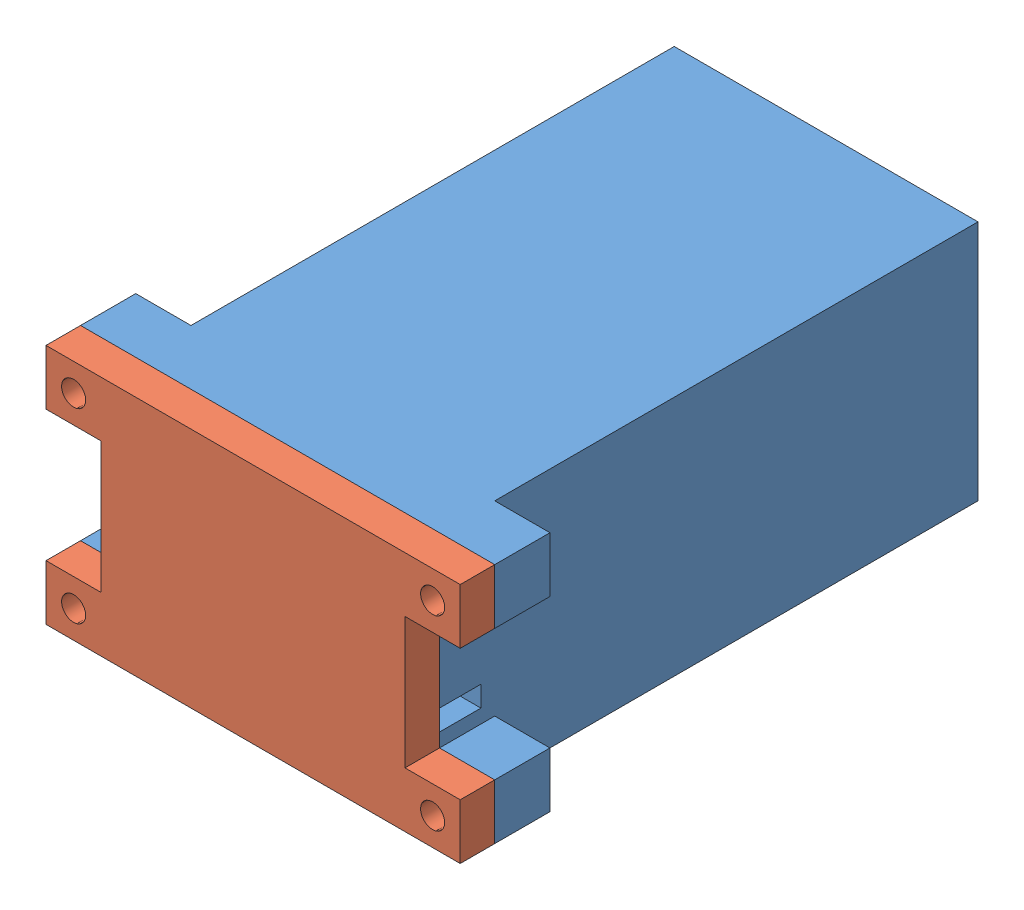
SolidWorks assembly battery_box_7V4, configuration 預設. Lengths in mm.
Overall size (60 33 83).
3 component instances, 3 part files, 5 mates.
Components (placement in the parent):
- battery_box_7V4-1: battery_box_7V4 [預設] at (4.9748 -22.7044 78) size (60 33 78)
- battery_cap_7V4-1: battery_cap_7V4 [預設] at (4.9748 -6.2044 117) size (60 33 5)
- battery7_4Vmodel-1: battery7_4Vmodel [預設] at (4.9748 -2.7044 74.5) x (0 0 1) z (0 -1 0) size (78 38 20)
Mates (geometry in assembly coordinates):
- 重合/共線/共點1: coincident aligned: circle of battery_box_7V4-1; circle of battery_cap_7V4-1
- 同軸心1: concentric anti-aligned: cylinder of battery_box_7V4-1 through (30.9748 6.2956 109) axis (0 0 1) radius 1.75; cylinder of battery_cap_7V4-1 through (30.9748 6.2956 122) axis (0 0 -1) radius 1.75
- 重合/共線/共點2: coincident anti-aligned: plane of battery_box_7V4-1 through (-14.0252 10.2956 39) normal (1 0 0); plane of battery7_4Vmodel-1 through (-14.0252 -12.7044 42) normal (-1 0 0)
- 重合/共線/共點3: coincident anti-aligned: plane of battery_box_7V4-1 through (4.9748 -12.7044 78) normal (0 1 0); plane of battery7_4Vmodel-1 through (4.9748 -12.7044 74.5) normal (0 -1 0)
- 重合/共線/共點4: coincident anti-aligned: plane of battery_box_7V4-1 through (-17.0252 10.2956 42) normal (0 0 1); plane of battery7_4Vmodel-1 through (-14.0252 -12.7044 42) normal (0 0 -1)
